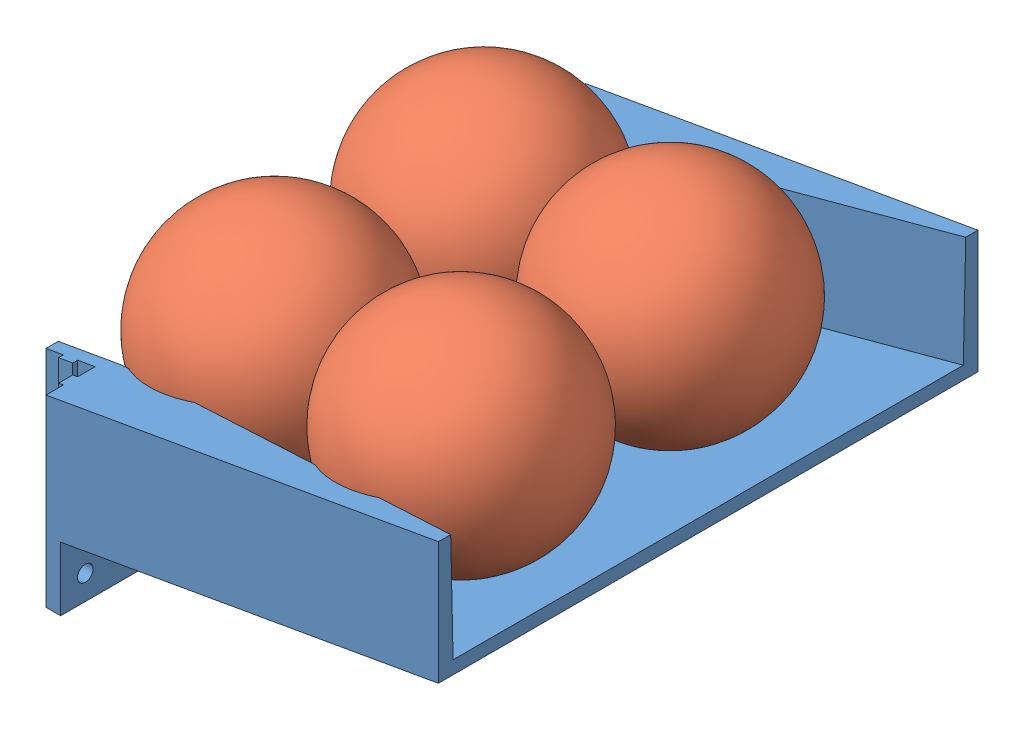
SolidWorks assembly DirtyWaterReleaserAssembly, configuration Default. Lengths in mm.
Overall size (97.34 73.31 110.37).
5 component instances, 2 part files, 9 mates.
Components (placement in the parent):
- DirtyWaterReleaser-1: DirtyWaterReleaser [Default] at (-139.6185 -11.48 43.4453) size (90 51.58 110)
- Ball2018-1: Ball2018 [Default] at (-116.6769 28.5268 22.0744) x (0.990326 0.025243 -0.136442) z (0.122777 -0.617551 0.776889) size (44.5 44.5 44.5)
- Ball2018-2: Ball2018 [Default] at (-73.1952 36.1938 27.6247) size (44.5 44.5 44.5)
- Ball2018-3: Ball2018 [Default] at (-114.8322 28.8521 66.535) x (0.934251 -0.312176 -0.172399) z (0.111319 -0.203987 0.972624) size (44.5 44.5 44.5)
- Ball2018-4: Ball2018 [Default] at (-71.3504 36.5191 72.0853) x (0.999633 0.015535 0.022184) z (-0.024028 0.130877 0.991107) size (44.5 44.5 44.5)
Mates (geometry in assembly coordinates):
- Tangent1: tangent anti-aligned: plane of DirtyWaterReleaser-1 through (-141.9046 1.4852 43.4453) normal (-0.173648 0.984808 0); sphere of Ball2018-1
- Tangent2: tangent anti-aligned: plane of DirtyWaterReleaser-1 through (-122.8438 4.8462 0.9453) normal (0.124864 0.022017 0.99193); sphere of Ball2018-1
- Tangent3: tangent anti-aligned: plane of DirtyWaterReleaser-1 through (-141.9046 1.4852 43.4453) normal (-0.173648 0.984808 0); sphere of Ball2018-3
- Tangent5: tangent anti-aligned: plane of DirtyWaterReleaser-1 through (-141.9046 1.4852 43.4453) normal (-0.173648 0.984808 0); sphere of Ball2018-2
- Tangent6: tangent anti-aligned: plane of DirtyWaterReleaser-1 through (-141.9046 1.4852 43.4453) normal (-0.173648 0.984808 0); sphere of Ball2018-4
- Tangent7: tangent anti-aligned: sphere of Ball2018-2; sphere of Ball2018-4
- Tangent8: tangent anti-aligned: sphere of Ball2018-1; sphere of Ball2018-3
- Tangent9: tangent anti-aligned: sphere of Ball2018-3; sphere of Ball2018-4
- Tangent10: tangent anti-aligned: sphere of Ball2018-1; sphere of Ball2018-2
